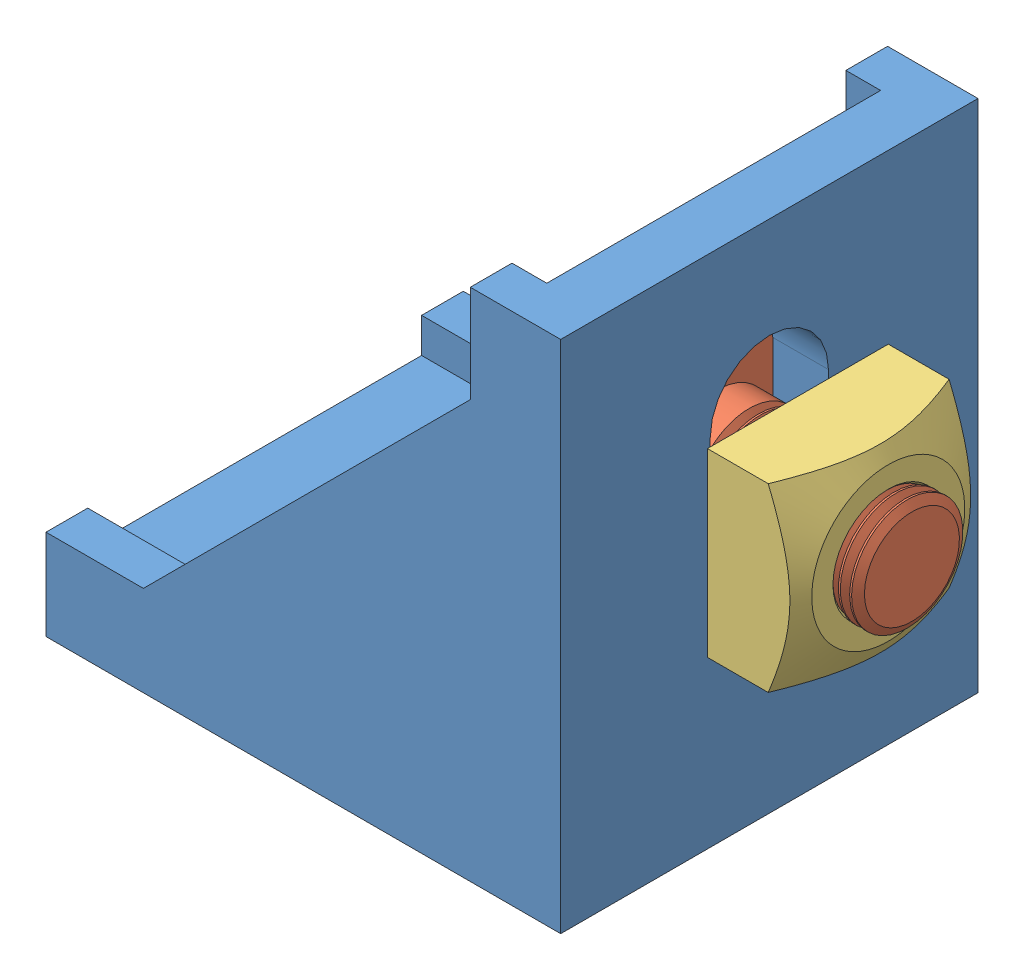
SolidWorks assembly 角码+螺栓, configuration 默认. Lengths in mm.
Overall size (47 47 30).
5 component instances, 3 part files, 10 mates.
Components (placement in the parent):
- 3030角码-1: 3030角码 [默认] at (-4.7227 -3.6958 22) size (37 37 30)
- hexagon socket button head screws gb-1: hexagon socket button head screws gb [GB_SOCKET_TYPE7 M8X14-S] at (3.2166 3.743 36.75) x (1 0 0) z (0 0.018323 0.999832) size (18.4 14 14)
- square nuts--product grade c gb-1: square nuts--product grade c gb [GB_SPECIAL_TYPE12 M8-C] at (19.9166 3.743 36.75) x (0 0.707107 -0.707107) z (1 0 0) size (18.38 18.38 6.5)
- hexagon socket button head screws gb-2: hexagon socket button head screws gb [GB_SOCKET_TYPE7 M8X14-S] at (-9.1015 -8.086 36.75) x (0 -1 0) z (-0.830458 0 -0.557081) size (18.4 14 14)
- square nuts--product grade c gb-2: square nuts--product grade c gb [GB_SPECIAL_TYPE12 M8-C] at (-9.1015 -24.786 36.75) x (0.707107 0 -0.707107) z (0 -1 0) size (18.38 18.38 6.5)
Mates (geometry in assembly coordinates):
- 相切2: tangent: plane of 3030角码-1 through (11.6166 9.014 32.75) normal (0 0 1); cylinder of hexagon socket button head screws gb-1 through (21.6166 3.743 36.75) axis (-1 0 0) radius 4
- 重合2: coincident: plane of 3030角码-1 through (7.6166 -3.6958 22) normal (-1 0 0); plane of hexagon socket button head screws gb-1 through (7.6166 3.743 36.75) normal (1 0 0)
- 同心1: concentric: cylinder of hexagon socket button head screws gb-1 through (21.6166 3.743 36.75) axis (-1 0 0) radius 4; cylinder of square nuts--product grade c gb-1 through (13.4166 3.743 36.75) axis (1 0 0) radius 3.4585
- 距离1: distance = 1.8 mm: plane of square nuts--product grade c gb-1 through (13.4166 10.243 30.25) normal (-1 0 0); plane of 3030角码-1 through (11.6166 20.514 52) normal (1 0 0)
- 平行1: parallel: plane of 3030角码-1 through (11.6166 20.514 52) normal (0 1 0); plane of square nuts--product grade c gb-1 through (13.4166 10.243 30.25) normal (0 1 0)
- 相切3: tangent: plane of 3030角码-1 through (-13.8834 -16.486 32.75) normal (0 0 1); cylinder of hexagon socket button head screws gb-2 through (-9.1015 -26.486 36.75) axis (0 1 0) radius 4
- 重合5: coincident: plane of 3030角码-1 through (7.6166 -12.486 25) normal (0 1 0); plane of hexagon socket button head screws gb-2 through (-9.1015 -12.486 36.75) normal (0 -1 0)
- 距离2: distance = 1.8 mm: plane of square nuts--product grade c gb-2 through (-2.6015 -18.286 30.25) normal (0 1 0); plane of 3030角码-1 through (-25.3834 -16.486 52) normal (0 -1 0)
- 同心2: concentric: cylinder of hexagon socket button head screws gb-2 through (-9.1015 -26.486 36.75) axis (0 1 0) radius 4; cylinder of square nuts--product grade c gb-2 through (-9.1015 -18.286 36.75) axis (0 -1 0) radius 3.4585
- 平行2: parallel: plane of 3030角码-1 through (-25.3834 -16.486 52) normal (-1 0 0); plane of square nuts--product grade c gb-2 through (-15.6015 -18.286 43.25) normal (-1 0 0)
